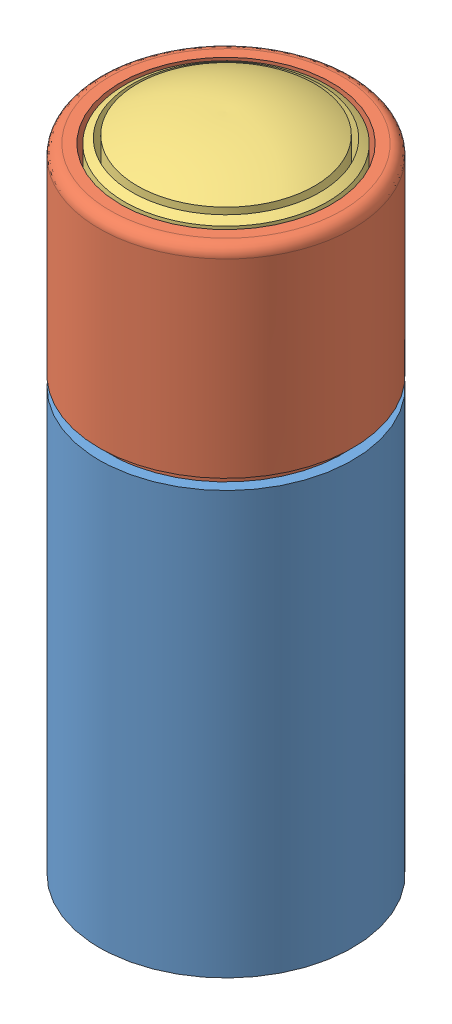
SolidWorks assembly laser guid pointer all, configuration Default. Lengths in mm.
Overall size (13.54 31.38 13.54).
3 component instances, 3 part files, 2 mates.
Components (placement in the parent):
- guide laser-1: guide laser [Default] at (11.8769 23.6764 17.6169) x (-1 0 0) z (0 0 1) size (12 20 12)
- guide laser head-1: guide laser head [Default] at (11.8769 23.6764 17.6169) x (0.990444 0 -0.137913) z (0.137913 0 0.990444) size (12 10 12)
- guide laser lense-1: guide laser lense [Default] at (13.5359 29.6764 22.1212) x (-0.345607 0 -0.938379) z (0.938379 0 -0.345607) size (9.6 5.38 9.6)
Mates (geometry in assembly coordinates):
- ProfileCenter1: profile center anti-aligned: plane of guide laser-1 through (11.8769 23.6764 17.6169) normal (0 1 0); plane of guide laser head-1 through (11.8769 23.6764 17.6169) normal (0 -1 0)
- ProfileCenter2: profile center anti-aligned: plane of guide laser lense-1 through (13.5359 29.6764 22.1212) normal (0 -1 0); plane of guide laser head-1 through (11.8769 29.6764 17.6169) normal (0 1 0)
